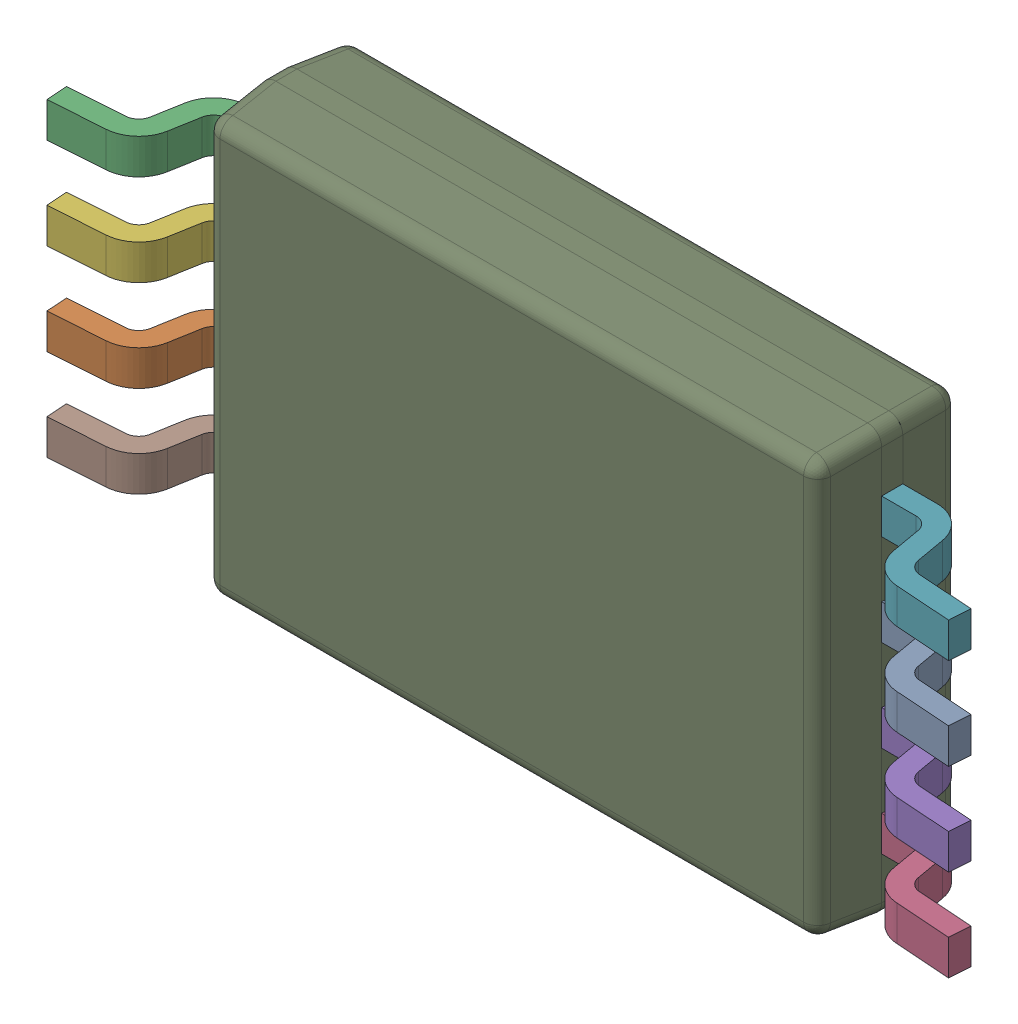
SolidWorks assembly IC10, configuration По умолчанию. Lengths in mm.
Overall size (6.42 3.01 1.1).
10 component instances, 2 part files, 0 mates.
Components (placement in the parent):
- PW0008A_ASM-1-1: PW0008A_ASM-1 [По умолчанию] at origin size (6.42 3.01 1.1)
  - PW0008A_ASM-Part-2-1: PW0008A_ASM-Part-2 [По умолчанию] at (2.575 0.325 -2.3511) x (0 -1 0) z (1 0 0) size (0.25 0.68 1.01)
  - PW0008A_ASM-Part-2-2: PW0008A_ASM-Part-2 [По умолчанию] at (-2.575 -0.325 -2.3511) x (0 1 0) z (-1 0 0) size (0.25 0.68 1.01)
  - PW0008A_ASM-Part-2-3: PW0008A_ASM-Part-2 [По умолчанию] at (-2.575 0.975 -2.3511) x (0 1 0) z (-1 0 0) size (0.25 0.68 1.01)
  - PW0008A_ASM-Part-2-4: PW0008A_ASM-Part-2 [По умолчанию] at (2.575 -0.975 -2.3511) x (0 -1 0) z (1 0 0) size (0.25 0.68 1.01)
  - PW0008A_ASM-Part-2-5: PW0008A_ASM-Part-2 [По умолчанию] at (2.575 -0.325 -2.3511) x (0 -1 0) z (1 0 0) size (0.25 0.68 1.01)
  - PW0008A_ASM-Part-2-6: PW0008A_ASM-Part-2 [По умолчанию] at (-2.575 0.325 -2.3511) x (0 1 0) z (-1 0 0) size (0.25 0.68 1.01)
  - PW0008A_ASM-Part-2-7: PW0008A_ASM-Part-2 [По умолчанию] at (2.575 0.975 -2.3511) x (0 -1 0) z (1 0 0) size (0.25 0.68 1.01)
  - PW0008A_ASM-Part-2-8: PW0008A_ASM-Part-2 [По умолчанию] at (-2.575 -0.975 -2.3511) x (0 1 0) z (-1 0 0) size (0.25 0.68 1.01)
  - PW0008A_ASM-Part-1-1-1: PW0008A_ASM-Part-1-1 [По умолчанию] at origin size (4.41 3.01 1)
